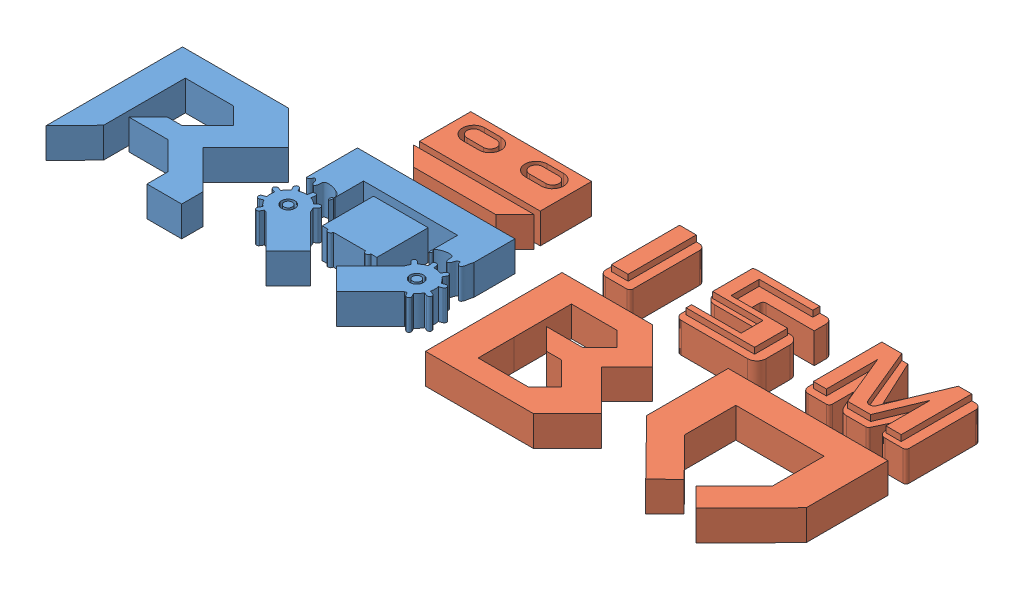
SolidWorks assembly FullLOGO, configuration Default. Lengths in mm.
Overall size (233.37 12 76.38).
2 component instances, 2 part files, 0 mates.
Components (placement in the parent):
- LOGO-1: LOGO [Default] at (57.1518 50.1714 98.4584) size (112.67 10 45.18)
- LOGO2-1: LOGO2 [Default] at (94.1302 48.2665 112.3477) size (169.03 12 76.38)
